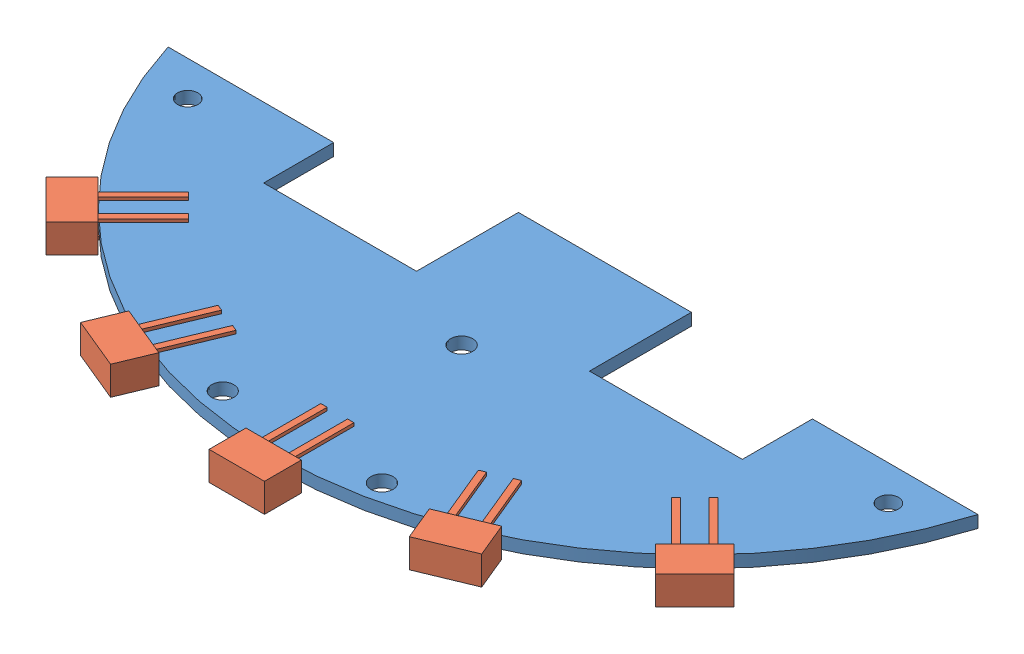
SolidWorks assembly CapteurPCB Avant, configuration Default. Lengths in mm.
Overall size (127.15 4.5 57.8).
6 component instances, 2 part files, 9 mates.
Components (placement in the parent):
- CapteurPCB Avant-1: CapteurPCB Avant [Default] at (0.1982 -11.99 -18.6785) size (127.15 1.9 52)
- RPR 359F-1: RPR 359F [Default] at (-50.9256 -11.04 58.5197) x (0.707107 0 -0.707107) z (0 -1 0) size (15.8 8.7 4.5)
- RPR 359F-2: RPR 359F [Default] at (-27.4698 -11.04 74.1923) x (0.382683 0 -0.92388) z (0 1 0) size (15.8 8.7 4.5)
- RPR 359F-3: RPR 359F [Default] at (0.1982 -11.04 79.6958) x (0 0 -1) z (0 1 0) size (15.8 8.7 4.5)
- RPR 359F-4: RPR 359F [Default] at (27.4698 -11.04 74.1923) x (-0.382683 0 -0.92388) z (0 -1 0) size (15.8 8.7 4.5)
- RPR 359F-5: RPR 359F [Default] at (50.9256 -11.04 58.5197) x (-0.707107 0 -0.707107) z (0 1 0) size (15.8 8.7 4.5)
Mates (geometry in assembly coordinates):
- Coincident1: coincident: plane of CapteurPCB Avant-1 through (0.1982 -10.09 -18.6785) normal (0 1 0); plane of RPR 359F-1 through (-36.5007 -10.09 47.7716) normal (0 -1 0)
- Coincident2: coincident: point of CapteurPCB Avant-1; line of RPR 359F-1 through (-46.8244 -13.29 54.4184) axis (0 1 0)
- Tangent1: tangent anti-aligned: cylinder of CapteurPCB Avant-1 through (0.1982 -10.09 7.3958) axis (0 -1 0) radius 66.5; plane of RPR 359F-1 through (-46.8244 -11.04 54.4184) normal (0.707107 0 -0.707107)
- Coincident3: coincident: point of CapteurPCB Avant-1; line of RPR 359F-2 through (-25.2503 -8.79 68.8338) axis (0 -1 0)
- Tangent2: tangent anti-aligned: cylinder of CapteurPCB Avant-1 through (0.1982 -10.09 7.3958) axis (0 -1 0) radius 66.5; plane of RPR 359F-2 through (-25.2503 -11.04 68.8338) normal (0.382683 0 -0.92388)
- Coincident4: coincident anti-aligned: plane of CapteurPCB Avant-1 through (0.1982 -10.09 -18.6785) normal (0 1 0); plane of RPR 359F-2 through (-23.0602 -10.09 56.7523) normal (0 -1 0)
- Coincident5: coincident: point of CapteurPCB Avant-1; line of RPR 359F-3 through (0.1982 -8.79 73.8958) axis (0 -1 0)
- Tangent3: tangent anti-aligned: cylinder of CapteurPCB Avant-1 through (0.1982 -10.09 7.3958) axis (0 -1 0) radius 66.5; plane of RPR 359F-3 through (0.1982 -11.04 73.8958) normal (0 0 -1)
- Coincident6: coincident anti-aligned: plane of CapteurPCB Avant-1 through (0.1982 -10.09 -18.6785) normal (0 1 0); plane of RPR 359F-3 through (2.7982 -10.09 61.8958) normal (0 -1 0)
